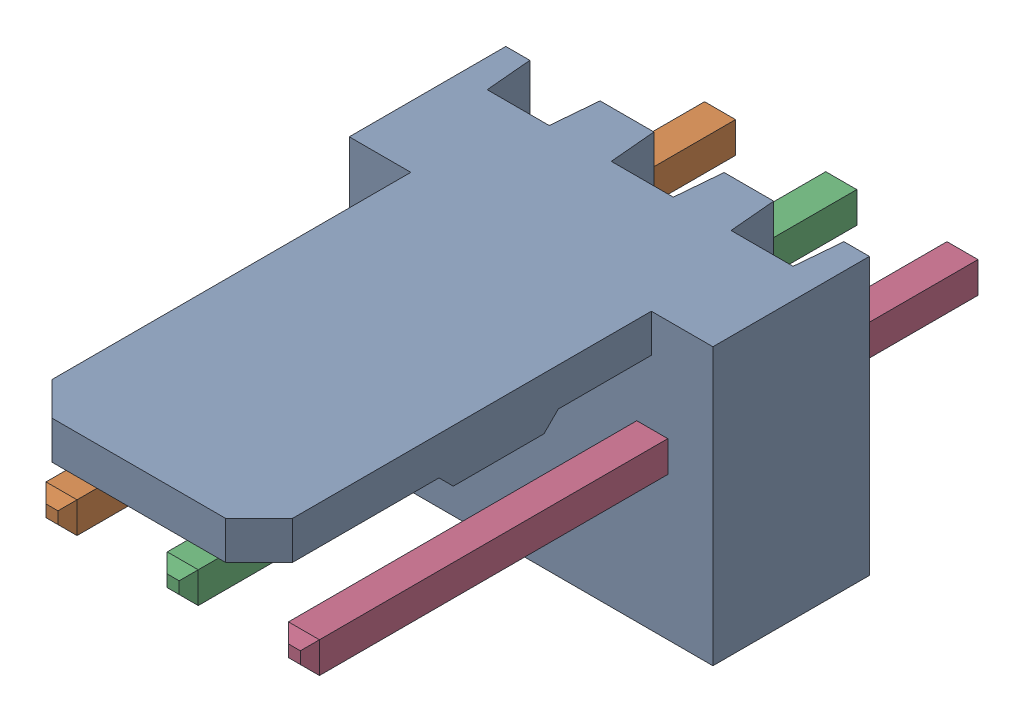
SolidWorks assembly Molex PCB 3 pin v2 v6 (4), configuration Default. Lengths in mm.
Overall size (7.62 5.79 14.92).
4 component instances, 2 part files, 0 mates.
Components (placement in the parent):
- BASE9710016 (1)-1: BASE9710016 (1) [Default] at (2.54 2.895 -8.22) size (7.62 5.79 11.5)
- PINO9710016 (1)-1: PINO9710016 (1) [Default] at (1.27 3.325 -0.72) size (0.65 0.65 14.2)
- PINO9710016 (1)-2: PINO9710016 (1) [Default] at (3.81 3.325 -0.72) size (0.65 0.65 14.2)
- PINO9710016 (1)-3: PINO9710016 (1) [Default] at (6.35 3.325 -0.72) size (0.65 0.65 14.2)
